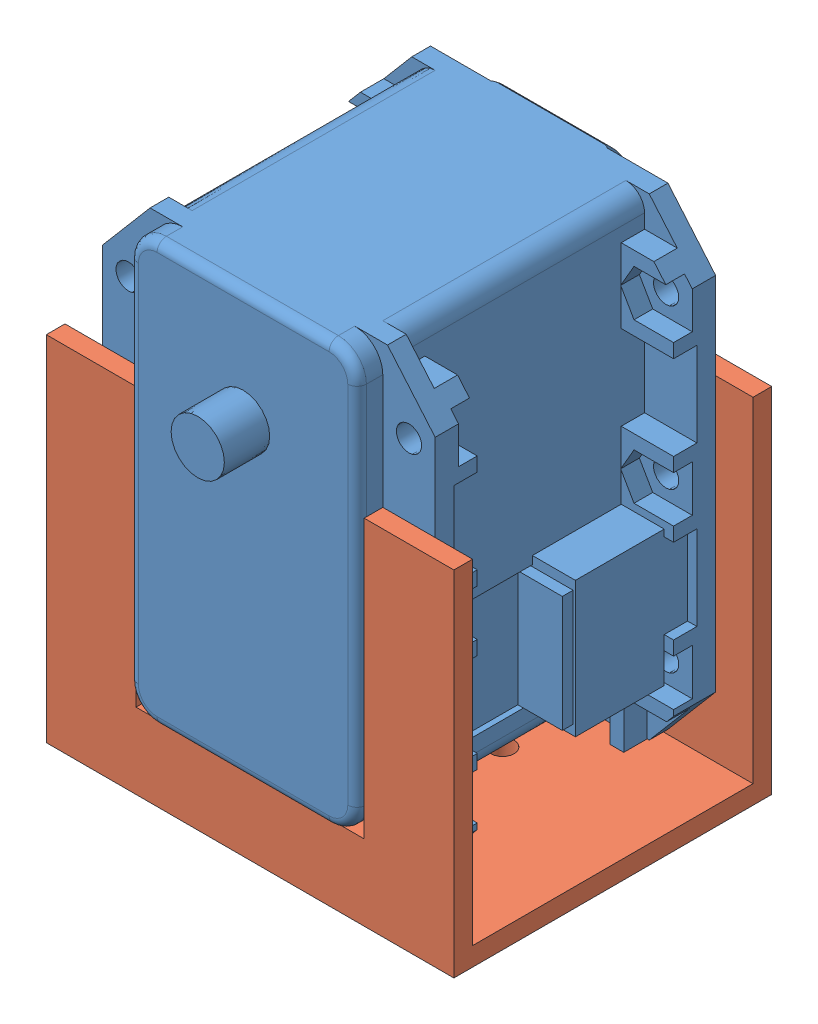
SolidWorks assembly Assem2, configuration Default. Lengths in mm.
Overall size (43.6 53.12 41.85).
2 component instances, 2 part files, 3 mates.
Components (placement in the parent):
- MX-28 SERVO-1: MX-28 SERVO [Default] at (20.8834 36.3383 38.4326) size (35.6 50.63 41.85)
- Bracket-1: Bracket [Default] at (20.8834 -4.7517 38.4326) size (43.6 37.8 34)
Mates (geometry in assembly coordinates):
- Coincident1: coincident: line of MX-28 SERVO-1 through (8.6834 6.3383 53.4326) axis (0 1 0); line of ? through (8.6834 20.925 53.4326) axis (0 -1 0)
- Coincident2: coincident: line of assembly; line of assembly; line of MX-28 SERVO-1 through (33.0834 45.3383 53.4326) axis (0 -1 0); line of Bracket-1 through (33.0834 33.0483 53.4326) axis (0 -1 0)
- Coincident3: coincident: line of assembly; line of assembly; line of MX-28 SERVO-1 through (30.0834 3.3383 53.4326) axis (-1 0 0); line of Bracket-1 through (33.0834 3.3383 53.4326) axis (-1 0 0)
